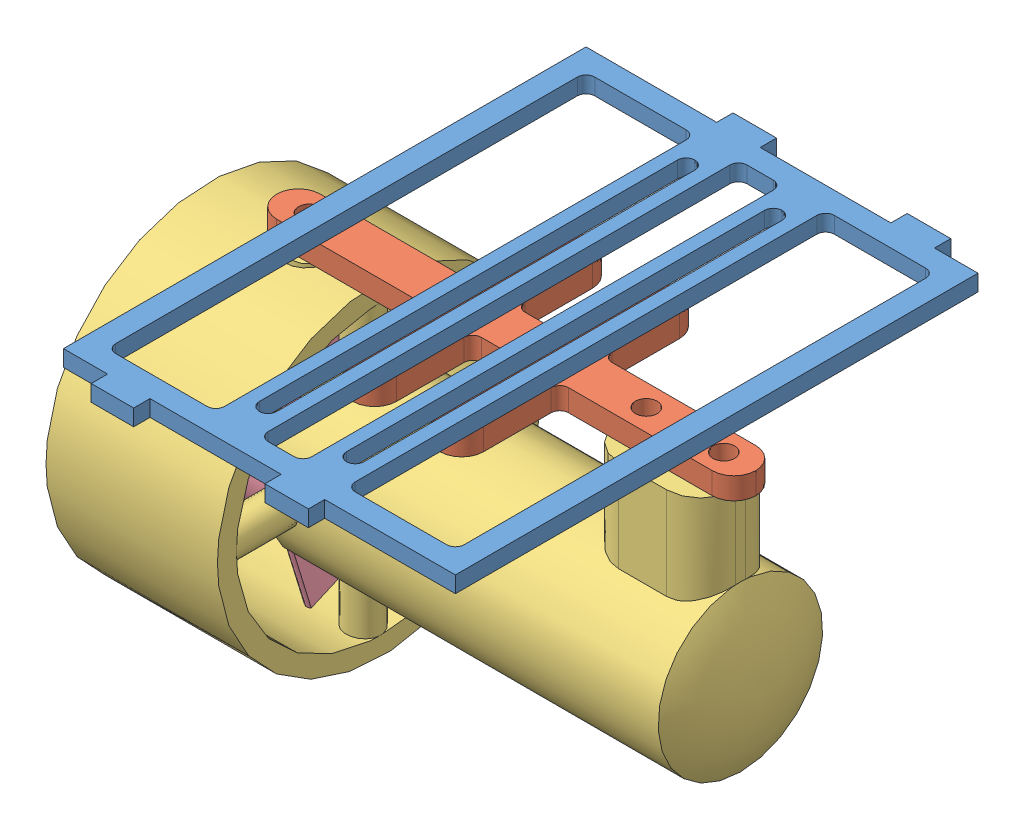
SolidWorks assembly S Thruster Panel, configuration Default. Lengths in mm.
Overall size (160.94 106.61 187.33).
5 component instances, 4 part files, 5 mates.
Components (placement in the parent):
- S Thruster Panel-1: S Thruster Panel [Default] at (-24.8567 24.3637 -5.0536) size (114.3 4.76 187.33)
- Thruster Adapter-1: Thruster Adapter [Default] at (-24.8567 18.0137 -3.7496) size (139.7 6.35 69.85)
- propeller-1: propeller [Default] at (-45.778 -12.7364 40.4279) x (0 0 1) z (1 0 0) size (95 95.5 160.94)
  - thruster-1: thruster [Default] at (-44.1774 17.2499 -68.7069) size (95 95.5 160.94)
  - propeller-1: propeller [Default] at (-44.1774 17.2499 -28.7069) x (0.293244 -0.956038 0) z (0 0 -1) size (76 40 35.82)
Mates (geometry in assembly coordinates):
- Concentric1: concentric anti-aligned: circle of Thruster Adapter-1; circle of propeller-1/thruster-1
- Coincident1: coincident anti-aligned: plane of Thruster Adapter-1 through (-94.7067 18.0137 2.6004) normal (0 -1 0); plane of propeller-1/thruster-1 through (-83.4335 18.0137 -5.2496) normal (0 1 0)
- Parallel1: parallel anti-aligned: line of Thruster Adapter-1 through (-3.2667 24.3637 2.6004) axis (1 0 0); line of propeller-1/thruster-1 through (30.5151 18.0137 7.7504) axis (-1 0 0)
- Coincident3: coincident anti-aligned: plane of S Thruster Panel-1 through (-82.0067 24.3637 83.8464) normal (0 -1 0); plane of Thruster Adapter-1 through (-94.7067 24.3637 2.6004) normal (0 1 0)
- Coincident4: coincident aligned: line of S Thruster Panel-1 through (-43.9067 24.3637 -85.6986) axis (0 0 1); line of Thruster Adapter-1 through (-43.9067 24.3637 -32.3246) axis (0 0 1)
